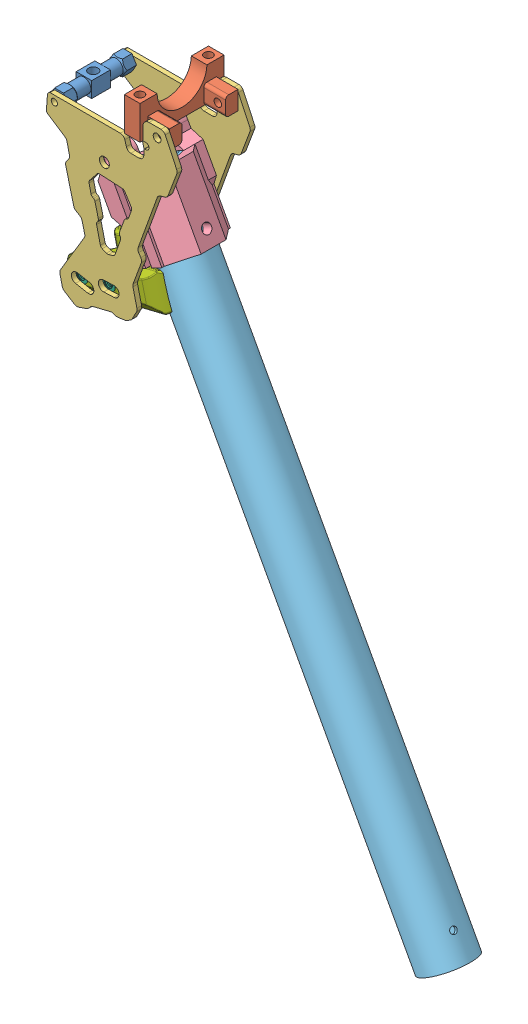
SolidWorks assembly landing, configuration Default. Lengths in mm.
Overall size (125.03 207.46 27).
12 component instances, 7 part files, 16 mates.
Components (placement in the parent):
- spacer landing gear 22mm-1: spacer landing gear 22mm [Default] at (7.212 24.6188 18.147) x (0 -1 0) z (1 0 0) size (5 22 5.77)
- side bracket bottom-1: side bracket bottom [Default] at (30.7117 39.2001 18.147) x (0 0 1) z (0 1 0) size (27 12 10.8)
- bracket landing gear-1: bracket landing gear [Default] at (26.961 -16.3909 5.647) size (41.97 62.78 1.5)
- bracket landing gear-2: bracket landing gear [Default] at (26.961 -16.3909 29.147) size (41.97 62.78 1.5)
- ArmCopterAttachement-1: ArmCopterAttachement [Default] at (36.2012 -7.7928 18.218) x (0 0 -1) z (-0.478386 0.87815 0) size (22.14 22.14 30.75)
- Carbon tube-1: Carbon tube [Default] at (121.3538 -164.1035 18.218) x (-0.132454 -0.072157 0.988559) z (-0.868103 -0.472913 -0.150833) size (16 200 16)
- 20021-003_arm-clip-1: 20021-003_arm-clip [Default] at (31.6755 -16.4929 18.147) x (0.971308 0.237826 0) z (0 0 1) size (30.85 11.33 22.06)
  - 94180A321_1-1: 94180A321_1 [Default] at (-17.8646 0 11) x (1 0 0) z (0 -1 0) size (4.37 3.46 4.37)
  - 94180A321_1-2: 94180A321_1 [Default] at (-8.8476 0 11) x (1 0 0) z (0 -1 0) size (4.37 3.46 4.37)
  - 94180A321_1-3: 94180A321_1 [Default] at (-8.8476 0 -11) x (1 0 0) z (0 1 0) size (4.37 3.46 4.37)
  - 94180A321_1-4: 94180A321_1 [Default] at (-17.8646 0 -11) x (1 0 0) z (0 1 0) size (4.37 3.46 4.37)
  - 20021-003_arm-clip v2-1: 20021-003_arm-clip v2 [Default] at (-0.993 0 0) size (30.85 11.33 22.03)
Mates (geometry in assembly coordinates):
- Concentric2: concentric aligned: cylinder of spacer landing gear 22mm-1 through (7.212 24.6188 7.147) axis (0 0 -1) radius 1.5; cylinder of bracket landing gear-1 through (7.212 24.6188 5.647) axis (0 0 -1) radius 1
- Coincident1: coincident anti-aligned: plane of spacer landing gear 22mm-1 through (7.212 24.6188 7.147) normal (0 0 -1); plane of bracket landing gear-1 through (25.7009 2.8901 7.147) normal (0 0 1)
- Coincident2: coincident anti-aligned: plane of spacer landing gear 22mm-1 through (7.212 24.6188 29.147) normal (0 0 1); plane of bracket landing gear-2 through (25.7009 2.8901 29.147) normal (0 0 -1)
- Concentric3: concentric aligned: cylinder of spacer landing gear 22mm-1 through (7.212 24.6188 7.147) axis (0 0 -1) radius 1.5; cylinder of bracket landing gear-2 through (7.212 24.6188 29.147) axis (0 0 -1) radius 1
- Concentric4: concentric aligned: cylinder of side bracket bottom-1 through (40.2117 31.2001 29.147) axis (0 0 -1) radius 1.21; cylinder of bracket landing gear-2 through (40.2117 31.2001 29.147) axis (0 0 -1) radius 1.25
- Coincident3: coincident aligned: plane of bracket landing gear-1 through (29.5173 26.6001 5.647) normal (0 1 0); plane of bracket landing gear-2 through (29.5173 26.6001 29.147) normal (0 1 0)
- Coincident4: coincident anti-aligned: plane of side bracket bottom-1 through (35.7117 34.2001 29.147) normal (0 0 1); plane of bracket landing gear-2 through (25.7009 2.8901 29.147) normal (0 0 -1)
- Parallel1: parallel aligned: plane of side bracket bottom-1 through (30.7117 28.2001 31.647) normal (0 -1 0); plane of bracket landing gear-2 through (35.6217 28.1001 29.147) normal (0 -1 0)
- Parallel2: parallel aligned: plane of spacer landing gear 22mm-1 through (4.712 27.1188 18.147) normal (0 1 0); plane of bracket landing gear-2 through (29.5173 26.6001 29.147) normal (0 1 0)
- Concentric5: concentric anti-aligned: cylinder of bracket landing gear-1 through (23.2848 15.9172 5.647) axis (0 0 -1) radius 1.6; cylinder of ArmCopterAttachement-1 through (23.2848 15.9172 23.0891) axis (0 0 1) radius 1.5
- Coincident7: coincident anti-aligned: plane of bracket landing gear-1 through (25.7009 2.8901 7.147) normal (0 0 1); plane of ArmCopterAttachement-1 through (22.1641 9.6129 7.147) normal (0 0 -1)
- Coincident8: coincident anti-aligned: plane of ArmCopterAttachement-1 through (25.6767 11.5264 18.218) normal (0.478386 -0.87815 0); circle of Carbon tube-1
- Concentric6: concentric aligned: cylinder of ArmCopterAttachement-1 through (25.6767 11.5264 18.218) axis (0.478386 -0.87815 0) radius 8; cylinder of Carbon tube-1 through (25.6767 11.5264 18.218) axis (0.478386 -0.87815 0) radius 8
- Concentric7: concentric anti-aligned: cylinder of bracket landing gear-2 through (14.3235 -20.7416 29.147) axis (0 0 1) radius 1.65; circle of 20021-003_arm-clip-1/20021-003_arm-clip v2-1
- Coincident9: coincident anti-aligned: plane of bracket landing gear-2 through (25.7009 2.8901 29.147) normal (0 0 -1); plane of 20021-003_arm-clip-1/20021-003_arm-clip v2-1 through (9.9594 -21.8101 29.147) normal (0 0 1)
- Parallel3: parallel aligned: plane of bracket landing gear-1 through (19.0497 -26.147 5.647) normal (0.237826 -0.971308 0); plane of 20021-003_arm-clip-1/20021-003_arm-clip v2-1 through (10.8822 -25.5788 29.147) normal (0.237826 -0.971308 0)
